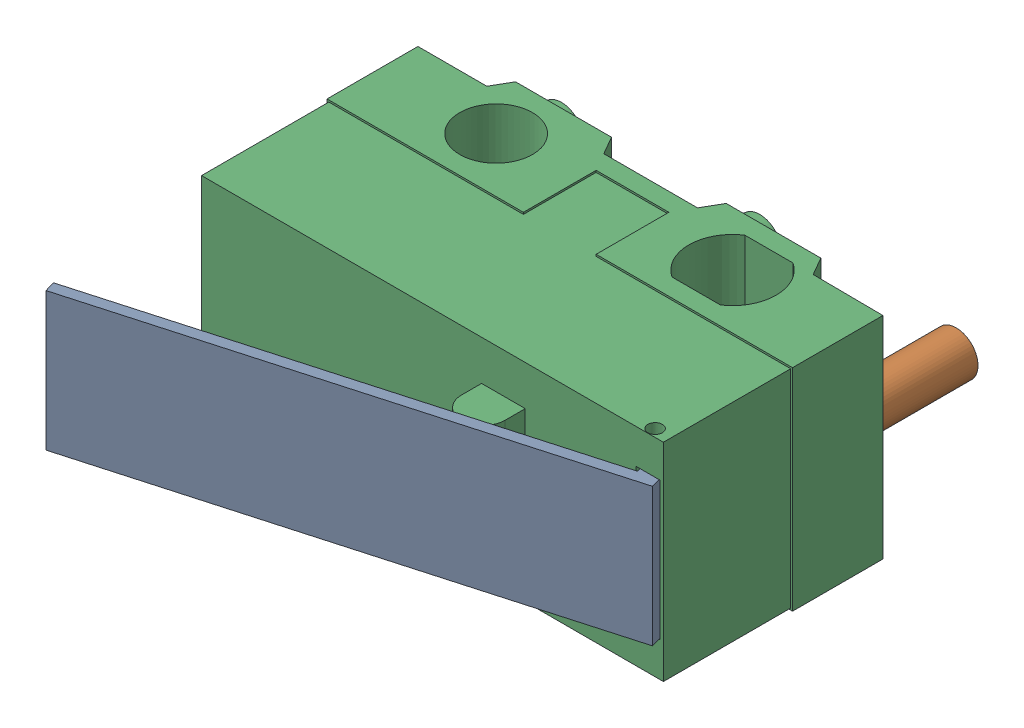
SolidWorks assembly KW10 Microswitch v2 v1_1, configuration Default. Lengths in mm.
Overall size (13.18 5.8 12.93).
5 component instances, 3 part files, 0 mates.
Components (placement in the parent):
- Component2_1-1: Component2_1 [Default] at (-0.4015 5 5) x (-1 0 0) z (0 0 1) size (13.18 5.8 12.93)
  - Component3_1-1: Component3_1 [Default] at origin size (13.08 3.8 4.39)
    - Component6-1: Component6 [Default] at origin size (13.08 3.8 4.39)
  - Component7-1: Component7 [Default] at origin size (1.2 1.2 3)
  - Component8-1: Component8 [Default] at origin size (12.8 5.8 10.15)
